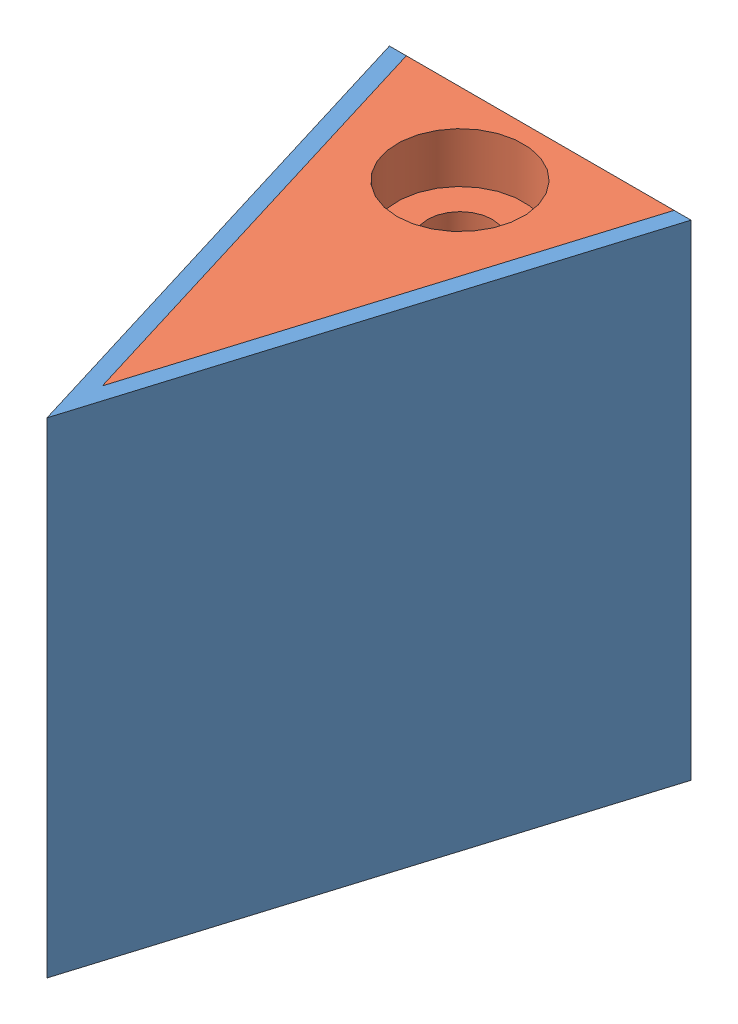
SolidWorks assembly Two Material Solenoid Insert 0.5, configuration Default. Lengths in mm.
Overall size (9.32 15 15.25).
2 component instances, 2 part files, 3 mates.
Components (placement in the parent):
- Solenoid Insert Tango Black 0.5-1: Solenoid Insert Tango Black 0.5 [Default] at (-3.175 0.3152 6.0007) size (9.32 15 15.25)
- Solenoid Insert Verowhite 0.5-1: Solenoid Insert Verowhite 0.5 [Default] at (-3.175 0.3152 6.0007) size (8.28 15 13.54)
Mates (geometry in assembly coordinates):
- Coincident1: coincident: line of Solenoid Insert Tango Black 0.5-1 through (-3.195 -2.1848 24.1059) axis (0 1 0); line of Solenoid Insert Verowhite 0.5-1 through (-3.195 -2.1848 24.1059) axis (0 1 0)
- Coincident2: coincident: plane of Solenoid Insert Tango Black 0.5-1 through (-3.175 12.8152 6.0007) normal (0 1 0); plane of Solenoid Insert Verowhite 0.5-1 through (-18.6586 12.8152 14.6892) normal (0 1 0)
- Coincident3: coincident anti-aligned: plane of Solenoid Insert Tango Black 0.5-1 through (-3.195 -2.1948 24.1059) normal (-0.956305 0 -0.292372); plane of Solenoid Insert Verowhite 0.5-1 through (-3.195 -2.1948 24.1059) normal (0.956305 0 0.292372)
